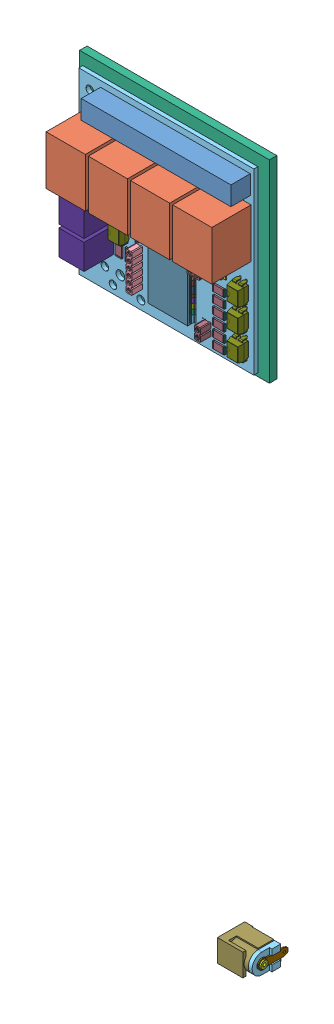
SolidWorks assembly Assem64, configuration Default. Lengths in mm.
Overall size (291.45 78 224.4).
194 component instances, 60 part files, 4 mates.
Components (placement in the parent):
- wifi_switch.STEP-1: wifi_switch.STEP [Default] at (-86.1181 -1.6116 -112.2386) size (288.45 72 221.81)
  - 8PIN_TERMINAL.STEP-1: 8PIN_TERMINAL.STEP [Default] at (-41 33.5 0.803) size (60.33 7.62 11.71)
    - Open CASCADE STEP translator 6.8 1.2.1.STEP-1: Open CASCADE STEP translator 6.8 1.2.1.STEP [Default] at origin size (60.33 7.62 11.71)
      - Body_1.STEP-1: Body_1.STEP [Default] at origin size (60.33 7.62 7.8)
      - Pin_1.STEP-1: Pin_1.STEP [Default] x (0 -1 0) z (0 0 1) size (1.42 1.42 8.52)
      - Pin_2.STEP-1: Pin_2.STEP [Default] at (5.0038 5.0038 0) x (0 -1 0) z (0 0 1) size (1.42 1.42 8.52)
      - Pin_3.STEP-1: Pin_3.STEP [Default] at (10.0076 10.0076 0) x (0 -1 0) z (0 0 1) size (1.42 1.42 8.52)
      - Pin_4.STEP-1: Pin_4.STEP [Default] at (15.0114 15.0114 0) x (0 -1 0) z (0 0 1) size (1.42 1.42 8.52)
      - Pin_5.STEP-1: Pin_5.STEP [Default] at (19.9898 19.9898 0) x (0 -1 0) z (0 0 1) size (1.42 1.42 8.52)
      - Pin_6.STEP-1: Pin_6.STEP [Default] at (24.9936 24.9936 0) x (0 -1 0) z (0 0 1) size (1.42 1.42 8.52)
      - Pin_7.STEP-1: Pin_7.STEP [Default] at (29.9974 29.9974 0) x (0 -1 0) z (0 0 1) size (1.42 1.42 8.52)
      - Pin_8.STEP-1: Pin_8.STEP [Default] at (35.0012 35.0012 0) x (0 -1 0) z (0 0 1) size (1.42 1.42 8.52)
      - Pin_9.STEP-1: Pin_9.STEP [Default] at (40.005 40.005 0) x (0 -1 0) z (0 0 1) size (1.42 1.42 8.52)
      - Pin_10.STEP-1: Pin_10.STEP [Default] at (45.0088 45.0088 0) x (0 -1 0) z (0 0 1) size (1.42 1.42 8.52)
      - Pin_11.STEP-1: Pin_11.STEP [Default] at (50.0126 50.0126 0) x (0 -1 0) z (0 0 1) size (1.42 1.42 8.52)
      - Pin_12.STEP-1: Pin_12.STEP [Default] at (54.991 54.991 0) x (0 -1 0) z (0 0 1) size (1.42 1.42 8.52)
  - ESP.STEP-1: ESP.STEP [Default] at (-5.5 -10.5 0.803) size (18.25 24 2.16)
    - Open CASCADE STEP translator 6.8 1.3.1.STEP-1: Open CASCADE STEP translator 6.8 1.3.1.STEP [Default] at origin size (18.25 24 2.16)
      - Body_1-0.STEP-1: Body_1-0.STEP [Default] at origin size (16 24 1.91)
      - Pin_1-1.STEP-1: Pin_1-1.STEP [Default] at origin size (1.12 2.9 1.33)
      - Pin_2-2.STEP-1: Pin_2-2.STEP [Default] at origin size (1.12 2.9 1.33)
      - Pin_3-3.STEP-1: Pin_3-3.STEP [Default] at origin size (1.12 2.9 1.33)
      - Pin_4-4.STEP-1: Pin_4-4.STEP [Default] at origin size (1.12 2.9 1.33)
      - Pin_5-5.STEP-1: Pin_5-5.STEP [Default] at origin size (1.12 2.9 1.33)
      - Pin_6-6.STEP-1: Pin_6-6.STEP [Default] at origin size (1.12 2.9 1.33)
      - Pin_7-7.STEP-1: Pin_7-7.STEP [Default] at origin size (1.12 2.9 1.33)
      - Pin_8-8.STEP-1: Pin_8-8.STEP [Default] at origin size (1.12 2.9 1.33)
      - Pin_9-9.STEP-1: Pin_9-9.STEP [Default] at (0 -28 0) x (-1 0 0) z (0 0 1) size (1.13 2.9 1.33)
      - Pin_10-10.STEP-1: Pin_10-10.STEP [Default] at (0 -24 0) x (-1 0 0) z (0 0 1) size (1.13 2.9 1.33)
      - Pin_11-11.STEP-1: Pin_11-11.STEP [Default] at (0 -20 0) x (-1 0 0) z (0 0 1) size (1.13 2.9 1.33)
      - Pin_12-12.STEP-1: Pin_12-12.STEP [Default] at (0 -16 0) x (-1 0 0) z (0 0 1) size (1.13 2.9 1.33)
      - Pin_13.STEP-1: Pin_13.STEP [Default] at (0 -12 0) x (-1 0 0) z (0 0 1) size (1.13 2.9 1.33)
      - Pin_14.STEP-1: Pin_14.STEP [Default] at (0 -8 0) x (-1 0 0) z (0 0 1) size (1.13 2.9 1.33)
      - Pin_15.STEP-1: Pin_15.STEP [Default] at (0 -4 0) x (-1 0 0) z (0 0 1) size (1.13 2.9 1.33)
      - Pin_16.STEP-1: Pin_16.STEP [Default] x (-1 0 0) z (0 0 1) size (1.13 2.9 1.33)
  - R1_470.STEP-1: R1_470.STEP [Default] at (-36 -18 0.803) x (0 1 0) z (0 0 1) size (4.78 2.7 0.65)
    - Open CASCADE STEP translator 6.8 1.4.1.STEP-1: Open CASCADE STEP translator 6.8 1.4.1.STEP [Default] at origin size (4.78 2.7 0.65)
      - Body_1-13.STEP-1: Body_1-13.STEP [Default] at origin size (4.4 2.68 0.63)
      - Pin_1-14.STEP-1: Pin_1-14.STEP [Default] at (0.374 0 0) x (-1 0 0) z (0 0 1) size (0.45 2.7 0.65)
      - Pin_2-15.STEP-1: Pin_2-15.STEP [Default] at origin size (0.45 2.7 0.65)
  - R3_470.STEP-1: R3_470.STEP [Default] at (2 -9.5 0.803) size (4.78 2.7 0.65)
    - Open CASCADE STEP translator 6.8 1.4.1.STEP-1: Open CASCADE STEP translator 6.8 1.4.1.STEP [Default] at origin size (4.78 2.7 0.65)
      - Body_1-13.STEP-1: Body_1-13.STEP [Default] at origin size (4.4 2.68 0.63)
      - Pin_1-14.STEP-1: Pin_1-14.STEP [Default] at (0.374 0 0) x (-1 0 0) z (0 0 1) size (0.45 2.7 0.65)
      - Pin_2-15.STEP-1: Pin_2-15.STEP [Default] at origin size (0.45 2.7 0.65)
  - R5_470.STEP-1: R5_470.STEP [Default] at (2 -13.5 0.803) size (4.78 2.7 0.65)
    - Open CASCADE STEP translator 6.8 1.4.1.STEP-1: Open CASCADE STEP translator 6.8 1.4.1.STEP [Default] at origin size (4.78 2.7 0.65)
      - Body_1-13.STEP-1: Body_1-13.STEP [Default] at origin size (4.4 2.68 0.63)
      - Pin_1-14.STEP-1: Pin_1-14.STEP [Default] at (0.374 0 0) x (-1 0 0) z (0 0 1) size (0.45 2.7 0.65)
      - Pin_2-15.STEP-1: Pin_2-15.STEP [Default] at origin size (0.45 2.7 0.65)
  - R7_470.STEP-1: R7_470.STEP [Default] at (2 -17.5 0.803) size (4.78 2.7 0.65)
    - Open CASCADE STEP translator 6.8 1.4.1.STEP-1: Open CASCADE STEP translator 6.8 1.4.1.STEP [Default] at origin size (4.78 2.7 0.65)
      - Body_1-13.STEP-1: Body_1-13.STEP [Default] at origin size (4.4 2.68 0.63)
      - Pin_1-14.STEP-1: Pin_1-14.STEP [Default] at (0.374 0 0) x (-1 0 0) z (0 0 1) size (0.45 2.7 0.65)
      - Pin_2-15.STEP-1: Pin_2-15.STEP [Default] at origin size (0.45 2.7 0.65)
  - OP1.STEP-1: OP1.STEP [Default] at (-35.5 -11 0.803) size (5.08 7.92 7.75)
    - Open CASCADE STEP translator 6.8 1.8.1.STEP-1: Open CASCADE STEP translator 6.8 1.8.1.STEP [Default] at origin size (5.08 7.92 7.75)
      - Body_1-16.STEP-1: Body_1-16.STEP [Default] at (1.3 3.7 0) x (0 1 0) z (1 0 0) size (7.92 7.75 5.08)
  - OP2.STEP-1: OP2.STEP [Default] at (12.5 -8.5 0.803) size (5.08 7.92 7.75)
    - Open CASCADE STEP translator 6.8 1.9.1.STEP-1: Open CASCADE STEP translator 6.8 1.9.1.STEP [Default] at origin size (5.08 7.92 7.75)
      - Body_1-16.STEP-1: Body_1-16.STEP [Default] at (1.3 3.7 0) x (0 1 0) z (1 0 0) size (7.92 7.75 5.08)
  - OP3.STEP-1: OP3.STEP [Default] at (12.5 -18 0.803) size (5.08 7.92 7.75)
    - Open CASCADE STEP translator 6.8 1.10.1.STEP-1: Open CASCADE STEP translator 6.8 1.10.1.STEP [Default] at origin size (5.08 7.92 7.75)
      - Body_1-16.STEP-1: Body_1-16.STEP [Default] at (1.3 3.7 0) x (0 1 0) z (1 0 0) size (7.92 7.75 5.08)
  - OP4.STEP-1: OP4.STEP [Default] at (12.5 -28 0.803) size (5.08 7.92 7.75)
    - Open CASCADE STEP translator 6.8 1.11.1.STEP-1: Open CASCADE STEP translator 6.8 1.11.1.STEP [Default] at origin size (5.08 7.92 7.75)
      - Body_1-16.STEP-1: Body_1-16.STEP [Default] at (1.3 3.7 0) x (0 1 0) z (1 0 0) size (7.92 7.75 5.08)
  - SMPS_5V_GND.STEP-1: SMPS_5V_GND.STEP [Default] at (-43.5 -4.5 0.803) x (0 1 0) z (0 0 1) size (10.16 10.16 15.71)
    - Open CASCADE STEP translator 6.8 1.12.1.STEP-1: Open CASCADE STEP translator 6.8 1.12.1.STEP [Default] at origin size (10.16 10.16 15.71)
      - Body_1-17.STEP-1: Body_1-17.STEP [Default] at origin size (10.16 10.16 11.8)
      - Pin_1-18.STEP-1: Pin_1-18.STEP [Default] x (0 -1 0) z (0 0 1) size (1.42 1.42 10.52)
      - Pin_2-19.STEP-1: Pin_2-19.STEP [Default] at (5.08 5.08 0) x (0 -1 0) z (0 0 1) size (1.42 1.42 10.52)
  - SMPS_L_N.STEP-1: SMPS_L_N.STEP [Default] at (-43.5 -16 0.803) x (0 1 0) z (0 0 1) size (10.16 10.16 15.71)
    - Open CASCADE STEP translator 6.8 1.12.1.STEP-1: Open CASCADE STEP translator 6.8 1.12.1.STEP [Default] at origin size (10.16 10.16 15.71)
      - Body_1-17.STEP-1: Body_1-17.STEP [Default] at origin size (10.16 10.16 11.8)
      - Pin_1-18.STEP-1: Pin_1-18.STEP [Default] x (0 -1 0) z (0 0 1) size (1.42 1.42 10.52)
      - Pin_2-19.STEP-1: Pin_2-19.STEP [Default] at (5.08 5.08 0) x (0 -1 0) z (0 0 1) size (1.42 1.42 10.52)
  - RL4.STEP-1: RL4.STEP [Default] at (-31 10 0.803) x (0 1 0) z (0 0 1) size (19.8 15.8 19.1)
    - Open CASCADE STEP translator 6.8 1.14.1.STEP-1: Open CASCADE STEP translator 6.8 1.14.1.STEP [Default] at origin size (19.8 15.8 19.1)
      - Body_1-20.STEP-1: Body_1-20.STEP [Default] at (6.5 -6 0) x (1 0 0) z (0 -1 0) size (19.8 19.1 15.8)
        - 1.STEP-1: 1.STEP [Default] at origin size (19.8 19.1 15.8)
        - 2.STEP-1: 2.STEP [Default] at origin size (1 4 0.4)
  - RL1.STEP-1: RL1.STEP [Default] at (-48 10 0.803) x (0 1 0) z (0 0 1) size (19.8 15.8 19.1)
    - Open CASCADE STEP translator 6.8 1.15.1.STEP-1: Open CASCADE STEP translator 6.8 1.15.1.STEP [Default] at origin size (19.8 15.8 19.1)
      - Body_1-1.STEP-1: Body_1-1.STEP [Default] at (6.5 -6 0) x (1 0 0) z (0 -1 0) size (19.8 19.1 15.8)
        - 1.STEP-1: 1.STEP [Default] at origin size (19.8 19.1 15.8)
        - 2.STEP-1: 2.STEP [Default] at origin size (1 4 0.4)
  - RL2.STEP-1: RL2.STEP [Default] at (-14 10 0.803) x (0 1 0) z (0 0 1) size (19.8 15.8 19.1)
    - Open CASCADE STEP translator 6.8 1.16.1.STEP-1: Open CASCADE STEP translator 6.8 1.16.1.STEP [Default] at origin size (19.8 15.8 19.1)
      - Body_1-2.STEP-1: Body_1-2.STEP [Default] at (6.5 -6 0) x (1 0 0) z (0 -1 0) size (19.8 19.1 15.8)
        - 1.STEP-1: 1.STEP [Default] at origin size (19.8 19.1 15.8)
        - 2.STEP-1: 2.STEP [Default] at origin size (1 4 0.4)
  - RL3.STEP-1: RL3.STEP [Default] at (3 10 0.803) x (0 1 0) z (0 0 1) size (19.8 15.8 19.1)
    - Open CASCADE STEP translator 6.8 1.17.1.STEP-1: Open CASCADE STEP translator 6.8 1.17.1.STEP [Default] at origin size (19.8 15.8 19.1)
      - Body_1-3.STEP-1: Body_1-3.STEP [Default] at (6.5 -6 0) x (1 0 0) z (0 -1 0) size (19.8 19.1 15.8)
        - 1.STEP-1: 1.STEP [Default] at origin size (19.8 19.1 15.8)
        - 2.STEP-1: 2.STEP [Default] at origin size (1 4 0.4)
  - DISPLAY_CONNECTOR.STEP-1: DISPLAY_CONNECTOR.STEP [Default] at (0 0 0.803) size (10.16 2.54 7.37)
    - Open CASCADE STEP translator 6.8 1.18.1.STEP-1: Open CASCADE STEP translator 6.8 1.18.1.STEP [Default] at origin size (10.16 2.54 7.37)
      - Body_1-21.STEP-1: Body_1-21.STEP [Default] at (3.8 0 0) x (1 0 0) z (0 -1 0) size (10.16 7.37 2.54)
  - DC_JACK.STEP-1: DC_JACK.STEP [Default] at (-42 -24.5 0.803) x (0 -1 0) z (0 0 1) size (9.5 14.51 14.4)
    - Open CASCADE STEP translator 6.8 1.19.1.STEP-1: Open CASCADE STEP translator 6.8 1.19.1.STEP [Default] at origin size (9.5 14.51 14.4)
      - Body_1-4.STEP-1: Body_1-4.STEP [Default] at (-1.97 277.95 212.6) x (-1 0 0) z (0 1 0) size (9.5 14.4 14.51)
        - =_[0_1_1_3].STEP-1: =_[0_1_1_3].STEP [Default] at origin size (8 10.5 2.55)
        - =_[0_1_1_4].STEP-1: =_[0_1_1_4].STEP [Default] at origin size (1.93 1.93 11.95)
        - =_[0_1_1_5].STEP-1: =_[0_1_1_5].STEP [Default] at origin size (3.3 3.3 1)
        - =_[0_1_1_6].STEP-1: =_[0_1_1_6].STEP [Default] at origin size (1.5 7.4 7.5)
        - =_[0_1_1_7].STEP-1: =_[0_1_1_7].STEP [Default] at origin size (4 12 0.5)
        - =_[0_1_1_8].STEP-1: =_[0_1_1_8].STEP [Default] at origin size (3.5 3.5 0.2)
        - =_[0_1_1_9].STEP-1: =_[0_1_1_9].STEP [Default] at origin size (2.5 3.7 0.2)
        - =_[0_1_1_10].STEP-1: =_[0_1_1_10].STEP [Default] at origin size (9 11 11.96)
  - RX.STEP-1: RX.STEP [Default] at (-3.5 -5 0.803) size (5.08 2.54 7.37)
    - Open CASCADE STEP translator 6.8 1.20.1.STEP-1: Open CASCADE STEP translator 6.8 1.20.1.STEP [Default] at origin size (5.08 2.54 7.37)
      - Body_1-22.STEP-1: Body_1-22.STEP [Default] at (1.3 0 0) x (1 0 0) z (0 -1 0) size (5.08 7.37 2.54)
  - Q1.STEP-1: Q1.STEP [Default] at (-34 1 0.803) size (4.8 20.44 3.83)
    - Open CASCADE STEP translator 6.8 1.21.1.STEP-1: Open CASCADE STEP translator 6.8 1.21.1.STEP [Default] at origin size (4.8 20.44 3.83)
      - Body_1-5.STEP-1: Body_1-5.STEP [Default] at origin size (4.8 20.44 3.83)
        - =_[0_1_1_3]-23.STEP-1: =_[0_1_1_3]-23.STEP [Default] at origin size (0.48 15.53 0.43)
        - =_[0_1_1_4]-24.STEP-1: =_[0_1_1_4]-24.STEP [Default] at origin size (0.49 15.53 0.43)
        - =_[0_1_1_5]-25.STEP-1: =_[0_1_1_5]-25.STEP [Default] at origin size (0.48 15.53 0.43)
        - =_[0_1_1_6]-26.STEP-1: =_[0_1_1_6]-26.STEP [Default] at origin size (4.8 4.95 3.83)
        - =_[0_1_1_7]-27.STEP-1: =_[0_1_1_7]-27.STEP [Default] at origin size (0.7 0.7 0.05)
  - Q2.STEP-1: Q2.STEP [Default] at (-10 1 0.803) size (4.8 20.44 3.83)
    - Open CASCADE STEP translator 6.8 1.22.1.STEP-1: Open CASCADE STEP translator 6.8 1.22.1.STEP [Default] at origin size (4.8 20.44 3.83)
      - Body_1-5.STEP-1: Body_1-5.STEP [Default] at origin size (4.8 20.44 3.83)
        - =_[0_1_1_3]-23.STEP-1: =_[0_1_1_3]-23.STEP [Default] at origin size (0.48 15.53 0.43)
        - =_[0_1_1_4]-24.STEP-1: =_[0_1_1_4]-24.STEP [Default] at origin size (0.49 15.53 0.43)
        - =_[0_1_1_5]-25.STEP-1: =_[0_1_1_5]-25.STEP [Default] at origin size (0.48 15.53 0.43)
        - =_[0_1_1_6]-26.STEP-1: =_[0_1_1_6]-26.STEP [Default] at origin size (4.8 4.95 3.83)
        - =_[0_1_1_7]-27.STEP-1: =_[0_1_1_7]-27.STEP [Default] at origin size (0.7 0.7 0.05)
  - Q3.STEP-1: Q3.STEP [Default] at (-16.5 1 0.803) size (4.8 20.44 3.83)
    - Open CASCADE STEP translator 6.8 1.23.1.STEP-1: Open CASCADE STEP translator 6.8 1.23.1.STEP [Default] at origin size (4.8 20.44 3.83)
      - Body_1-5.STEP-1: Body_1-5.STEP [Default] at origin size (4.8 20.44 3.83)
        - =_[0_1_1_3]-23.STEP-1: =_[0_1_1_3]-23.STEP [Default] at origin size (0.48 15.53 0.43)
        - =_[0_1_1_4]-24.STEP-1: =_[0_1_1_4]-24.STEP [Default] at origin size (0.49 15.53 0.43)
        - =_[0_1_1_5]-25.STEP-1: =_[0_1_1_5]-25.STEP [Default] at origin size (0.48 15.53 0.43)
        - =_[0_1_1_6]-26.STEP-1: =_[0_1_1_6]-26.STEP [Default] at origin size (4.8 4.95 3.83)
        - =_[0_1_1_7]-27.STEP-1: =_[0_1_1_7]-27.STEP [Default] at origin size (0.7 0.7 0.05)
  - Q4.STEP-1: Q4.STEP [Default] at (-22.5 1 0.803) size (4.8 20.44 3.83)
    - Open CASCADE STEP translator 6.8 1.24.1.STEP-1: Open CASCADE STEP translator 6.8 1.24.1.STEP [Default] at origin size (4.8 20.44 3.83)
      - Body_1-5.STEP-1: Body_1-5.STEP [Default] at origin size (4.8 20.44 3.83)
        - =_[0_1_1_3]-23.STEP-1: =_[0_1_1_3]-23.STEP [Default] at origin size (0.48 15.53 0.43)
        - =_[0_1_1_4]-24.STEP-1: =_[0_1_1_4]-24.STEP [Default] at origin size (0.49 15.53 0.43)
        - =_[0_1_1_5]-25.STEP-1: =_[0_1_1_5]-25.STEP [Default] at origin size (0.48 15.53 0.43)
        - =_[0_1_1_6]-26.STEP-1: =_[0_1_1_6]-26.STEP [Default] at origin size (4.8 4.95 3.83)
        - =_[0_1_1_7]-27.STEP-1: =_[0_1_1_7]-27.STEP [Default] at origin size (0.7 0.7 0.05)
  - R2_120.STEP-1: R2_120.STEP [Default] at (-32 -18 0.803) x (0 1 0) z (0 0 1) size (4.78 2.7 0.65)
    - Open CASCADE STEP translator 6.8 1.4.1.STEP-1: Open CASCADE STEP translator 6.8 1.4.1.STEP [Default] at origin size (4.78 2.7 0.65)
      - Body_1-13.STEP-1: Body_1-13.STEP [Default] at origin size (4.4 2.68 0.63)
      - Pin_1-14.STEP-1: Pin_1-14.STEP [Default] at (0.374 0 0) x (-1 0 0) z (0 0 1) size (0.45 2.7 0.65)
      - Pin_2-15.STEP-1: Pin_2-15.STEP [Default] at origin size (0.45 2.7 0.65)
  - R4_120.STEP-1: R4_120.STEP [Default] at (2 -21.5 0.803) size (4.78 2.7 0.65)
    - Open CASCADE STEP translator 6.8 1.4.1.STEP-1: Open CASCADE STEP translator 6.8 1.4.1.STEP [Default] at origin size (4.78 2.7 0.65)
      - Body_1-13.STEP-1: Body_1-13.STEP [Default] at origin size (4.4 2.68 0.63)
      - Pin_1-14.STEP-1: Pin_1-14.STEP [Default] at (0.374 0 0) x (-1 0 0) z (0 0 1) size (0.45 2.7 0.65)
      - Pin_2-15.STEP-1: Pin_2-15.STEP [Default] at origin size (0.45 2.7 0.65)
  - R6_120.STEP-1: R6_120.STEP [Default] at (2 -25.5 0.803) size (4.78 2.7 0.65)
    - Open CASCADE STEP translator 6.8 1.4.1.STEP-1: Open CASCADE STEP translator 6.8 1.4.1.STEP [Default] at origin size (4.78 2.7 0.65)
      - Body_1-13.STEP-1: Body_1-13.STEP [Default] at origin size (4.4 2.68 0.63)
      - Pin_1-14.STEP-1: Pin_1-14.STEP [Default] at (0.374 0 0) x (-1 0 0) z (0 0 1) size (0.45 2.7 0.65)
      - Pin_2-15.STEP-1: Pin_2-15.STEP [Default] at origin size (0.45 2.7 0.65)
  - R8_120.STEP-1: R8_120.STEP [Default] at (2 -29.5 0.803) size (4.78 2.7 0.65)
    - Open CASCADE STEP translator 6.8 1.4.1.STEP-1: Open CASCADE STEP translator 6.8 1.4.1.STEP [Default] at origin size (4.78 2.7 0.65)
      - Body_1-13.STEP-1: Body_1-13.STEP [Default] at origin size (4.4 2.68 0.63)
      - Pin_1-14.STEP-1: Pin_1-14.STEP [Default] at (0.374 0 0) x (-1 0 0) z (0 0 1) size (0.45 2.7 0.65)
      - Pin_2-15.STEP-1: Pin_2-15.STEP [Default] at origin size (0.45 2.7 0.65)
  - PN1.STEP-1: PN1.STEP [Default] at (-28.5 1 0.803) size (3.05 1.5 2.16)
    - Open CASCADE STEP translator 6.8 1.29.1.STEP-1: Open CASCADE STEP translator 6.8 1.29.1.STEP [Default] at origin size (3.05 1.5 2.16)
      - Body_1-28.STEP-1: Body_1-28.STEP [Default] at origin size (0.4 0.8 1.91)
      - Pin_1-29.STEP-1: Pin_1-29.STEP [Default] at origin size (1.32 1.5 1.33)
      - Pin_2-30.STEP-1: Pin_2-30.STEP [Default] at (2.8 0 0) x (-1 0 0) z (0 0 1) size (1.32 1.5 1.33)
  - PN2.STEP-1: PN2.STEP [Default] at (-27.5 -3 0.803) size (3.05 1.5 2.16)
    - Open CASCADE STEP translator 6.8 1.29.1.STEP-1: Open CASCADE STEP translator 6.8 1.29.1.STEP [Default] at origin size (3.05 1.5 2.16)
      - Body_1-28.STEP-1: Body_1-28.STEP [Default] at origin size (0.4 0.8 1.91)
      - Pin_1-29.STEP-1: Pin_1-29.STEP [Default] at origin size (1.32 1.5 1.33)
      - Pin_2-30.STEP-1: Pin_2-30.STEP [Default] at (2.8 0 0) x (-1 0 0) z (0 0 1) size (1.32 1.5 1.33)
  - PN3.STEP-1: PN3.STEP [Default] at (-27.5 -7.5 0.803) size (3.05 1.5 2.16)
    - Open CASCADE STEP translator 6.8 1.29.1.STEP-1: Open CASCADE STEP translator 6.8 1.29.1.STEP [Default] at origin size (3.05 1.5 2.16)
      - Body_1-28.STEP-1: Body_1-28.STEP [Default] at origin size (0.4 0.8 1.91)
      - Pin_1-29.STEP-1: Pin_1-29.STEP [Default] at origin size (1.32 1.5 1.33)
      - Pin_2-30.STEP-1: Pin_2-30.STEP [Default] at (2.8 0 0) x (-1 0 0) z (0 0 1) size (1.32 1.5 1.33)
  - PN4.STEP-1: PN4.STEP [Default] at (5.5 -4 0.803) size (3.05 1.5 2.16)
    - Open CASCADE STEP translator 6.8 1.29.1.STEP-1: Open CASCADE STEP translator 6.8 1.29.1.STEP [Default] at origin size (3.05 1.5 2.16)
      - Body_1-28.STEP-1: Body_1-28.STEP [Default] at origin size (0.4 0.8 1.91)
      - Pin_1-29.STEP-1: Pin_1-29.STEP [Default] at origin size (1.32 1.5 1.33)
      - Pin_2-30.STEP-1: Pin_2-30.STEP [Default] at (2.8 0 0) x (-1 0 0) z (0 0 1) size (1.32 1.5 1.33)
  - PROG.STEP-1: PROG.STEP [Default] at (-28.103 -24 0.803) x (0 1 0) z (0 0 1) size (15.24 2.54 7.37)
    - Open CASCADE STEP translator 6.8 1.33.1.STEP-1: Open CASCADE STEP translator 6.8 1.33.1.STEP [Default] at origin size (15.24 2.54 7.37)
      - Body_1-31.STEP-1: Body_1-31.STEP [Default] at (6.5 0 0) x (1 0 0) z (0 -1 0) size (15.24 7.37 2.54)
  - RESET.STEP-1: RESET.STEP [Default] at (-0.5 -26.5 0.803) x (0 1 0) z (0 0 1) size (5.08 2.54 7.37)
    - Open CASCADE STEP translator 6.8 1.34.1.STEP-1: Open CASCADE STEP translator 6.8 1.34.1.STEP [Default] at origin size (5.08 2.54 7.37)
      - Body_1-22.STEP-1: Body_1-22.STEP [Default] at (1.3 0 0) x (1 0 0) z (0 -1 0) size (5.08 7.37 2.54)
  - Layer_1.STEP-1: Layer_1.STEP [Default] at origin size (70.5 72 1.61)
- Part120^Assem64-1: Part120^Assem64 [Default] at (-94.1181 14.8884 -114.7356) x (0 -1 0) z (0 0 -1) size (78 76.5 3) (virtual)
Mates (geometry in assembly coordinates):
- InPlace1: in place: plane of ? through (-94.1181 6.3884 -114.7356) normal (0 0 -1); plane of ? through (0 0 -114.7356) normal (0 0 -1); moOrthogonalPlaneRef_w of ? through (-94.1181 6.3884 -114.7356) normal (0 0 -1); plane of ? through (0 0 -114.7356) normal (0 1 0); plane of ? through (-94.1181 6.3884 -114.7356) normal (0 0 -1); plane of ? through (0 0 -114.7356) normal (-1 0 0); plane of ? through (-94.1181 6.3884 -114.7356) normal (0 0 -1); unknown of Part120^Assem64-1
- Coincident1: coincident aligned: plane of wifi_switch.STEP-1/RL2.STEP-1/Open CASCADE STEP translator 6.8 1.16.1.STEP-1/Body_1-2.STEP-1/1.STEP-1; plane of Part120^Assem64-1
- Coincident2: coincident aligned: moOrthogonalPlaneRef_w of wifi_switch.STEP-1/RL2.STEP-1/Open CASCADE STEP translator 6.8 1.16.1.STEP-1/Body_1-2.STEP-1/1.STEP-1 through (-94.1181 14.8884 -114.7356) normal (-1 0 0); plane of Part120^Assem64-1 through (-94.1181 14.8884 -114.7356) normal (-1 0 0)
- Coincident3: coincident anti-aligned: moOrthogonalPlaneRef_w of wifi_switch.STEP-1/RL2.STEP-1/Open CASCADE STEP translator 6.8 1.16.1.STEP-1/Body_1-2.STEP-1/1.STEP-1 through (-94.1181 14.8884 -114.7356) normal (0 1 0); plane of Part120^Assem64-1 through (-94.1181 14.8884 -114.7356) normal (0 -1 0)
